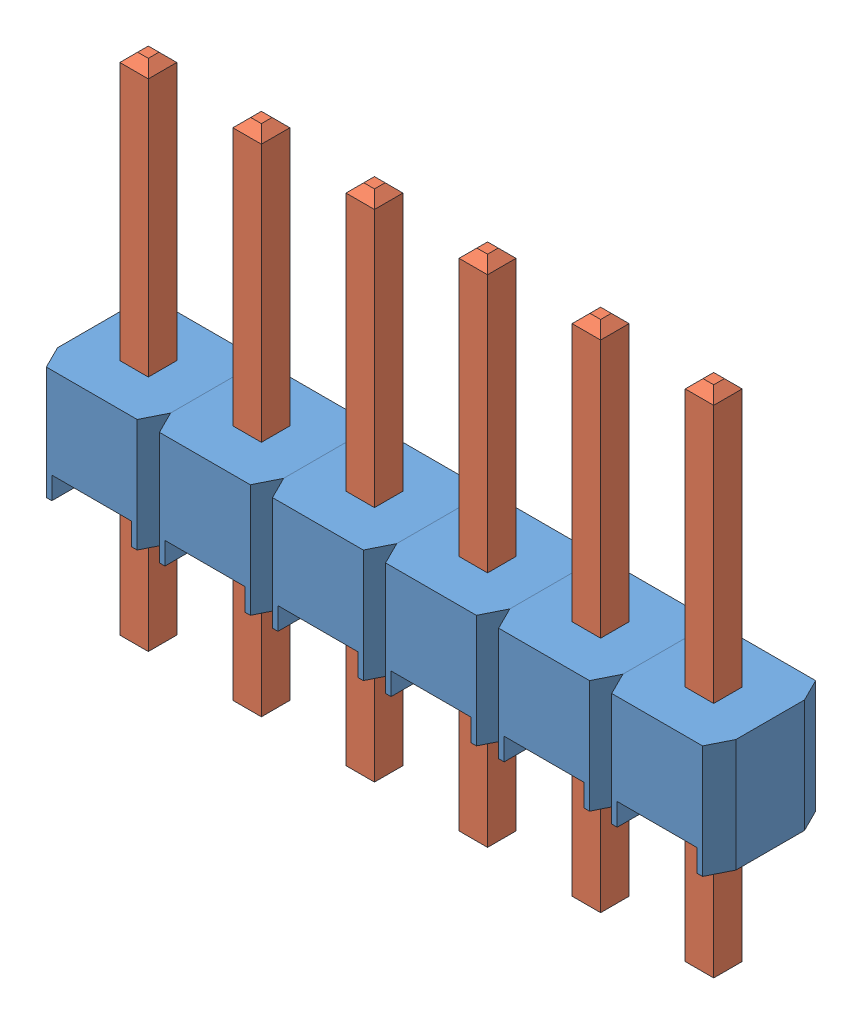
SolidWorks assembly Headers for dagaya motors, configuration 3pin. Lengths in mm.
Overall size (15.24 11.54 2.54).
12 component instances, 2 part files, 3 mates.
Components (placement in the parent):
- PlasticHolder-1: PlasticHolder [Default] at (0.8273 2.9943 2.6053) x (1 0 0) z (0 0 -1)
- SinglePinStraight-1: SinglePinStraight [Default] at (0.8273 -2.5457 2.6053)
- SinglePinStraight-2: SinglePinStraight [Default] at (3.3673 -2.5457 2.6053)
- PlasticHolder-2: PlasticHolder [Default] at (3.3673 2.9943 2.6053) x (1 0 0) z (0 0 -1)
- PlasticHolder-3: PlasticHolder [Default] at (5.9073 2.9943 2.6053) x (1 0 0) z (0 0 -1)
- SinglePinStraight-3: SinglePinStraight [Default] at (5.9073 -2.5457 2.6053)
- PlasticHolder-4: PlasticHolder [Default] at (8.4473 2.9943 2.6053) x (1 0 0) z (0 0 -1)
- SinglePinStraight-4: SinglePinStraight [Default] at (8.4473 -2.5457 2.6053)
- PlasticHolder-5: PlasticHolder [Default] at (10.9873 2.9943 2.6053) x (1 0 0) z (0 0 -1)
- SinglePinStraight-5: SinglePinStraight [Default] at (10.9873 -2.5457 2.6053)
- PlasticHolder-6: PlasticHolder [Default] at (13.5273 2.9943 2.6053) x (1 0 0) z (0 0 -1)
- SinglePinStraight-6: SinglePinStraight [Default] at (13.5273 -2.5457 2.6053)
Mates (geometry in assembly coordinates):
- Distance1: distance = 6 mm: plane of SinglePinStraight-1 through (0.8273 8.9943 2.6053) normal (0 1 0); plane of PlasticHolder-1 through (0.8273 2.9943 2.6053) normal (0 1 0)
- Coincident2: coincident: line of PlasticHolder-1 through (0.5073 0.9543 2.2853) axis (0 1 0); line of SinglePinStraight-1 through (0.5073 8.7943 2.2853) axis (0 -1 0)
- Coincident4: coincident: line of PlasticHolder-1 through (1.1473 0.9543 2.2853) axis (0 1 0); line of SinglePinStraight-1 through (1.1473 8.7943 2.2853) axis (0 -1 0)
